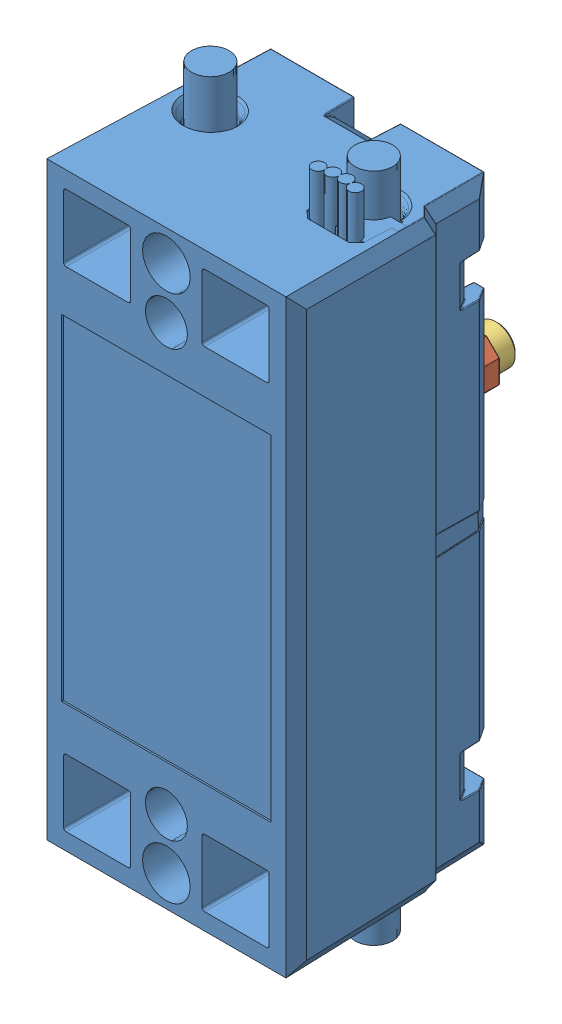
SolidWorks assembly Motor Controller, Talon SRX, configuration Default. Lengths in mm.
Overall size (30.47 80 30.19).
4 component instances, 3 part files, 0 mates.
Components (placement in the parent):
- 217-8080-baseRev4_no wires-1: 217-8080-baseRev4_no wires [Default] at origin size (30.47 80 25.21)
- 217-8080-002 Rev1-1: 217-8080-002 Rev1 [Default] at (0 13.05 -9.65) x (1 0 0) z (0 -1 0) size (25.15 2.91 7.5)
- 217-8080-005 Rev1_91251A105-1: 217-8080-005 Rev1_91251A105 [Default] at (-9.525 13.05 -5.8875) size (4.65 4.65 7.74)
- 217-8080-005 Rev1_91251A105-2: 217-8080-005 Rev1_91251A105 [Default] at (9.525 13.05 -5.8875) size (4.65 4.65 7.74)
